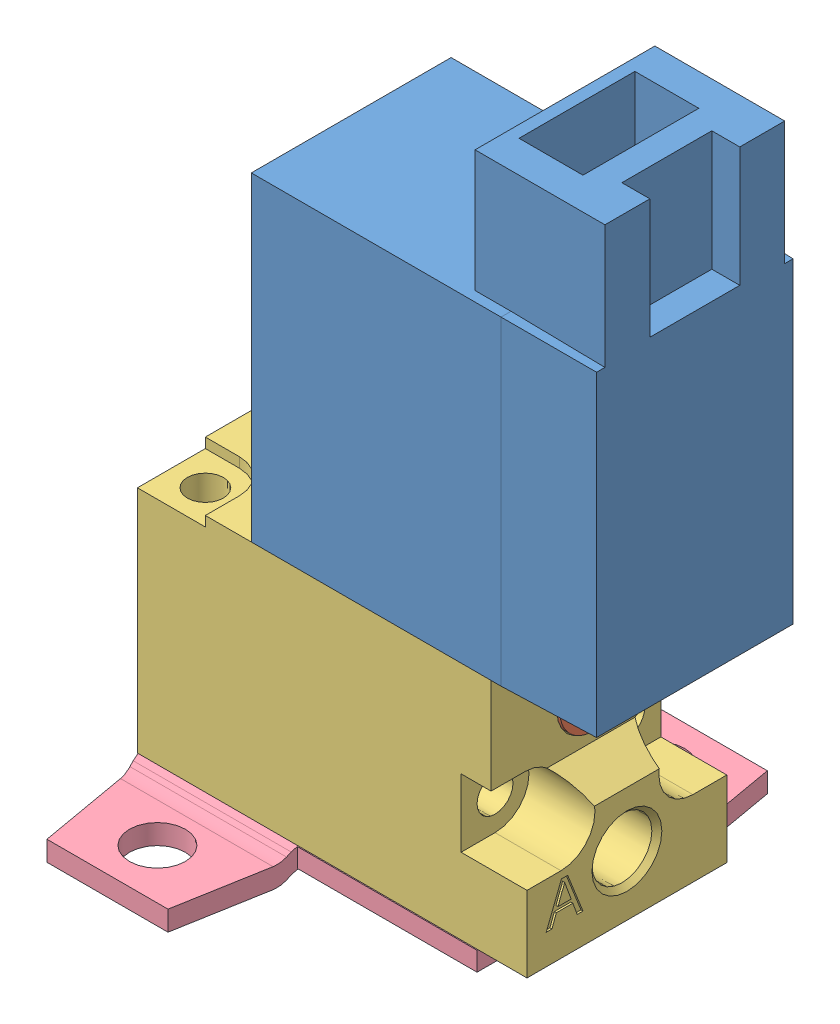
SolidWorks assembly SY113-SMO-PM3-F, configuration Default. Lengths in mm.
Overall size (22.9 35.6 21).
4 component instances, 4 part files, 0 mates.
Components (placement in the parent):
- SY113-SMO-PM3-F.step_1115coil_MDC-1: SY113-SMO-PM3-F.step_1115coil_MDC [Default] at (13.2 12 0) size (17.2 22.1 10)
- SY113-SMO-PM3-F.step_MAN-OPA_P-1: SY113-SMO-PM3-F.step_MAN-OPA_P [Default] at (12.3 9 0) x (0 0 -1) z (0 -1 0) size (3.3 0.5 3.3)
- SY113-SMO-PM3-F.step_1115valvebase_BPP-1: SY113-SMO-PM3-F.step_1115valvebase_BPP [Default] at origin size (19.5 12 10)
- SY113-SMO-PM3-F.step_1115bracket-1: SY113-SMO-PM3-F.step_1115bracket [Default] at (-5 0 0) x (-1 0 0) z (0 0 -1) size (17 1.5 21)
